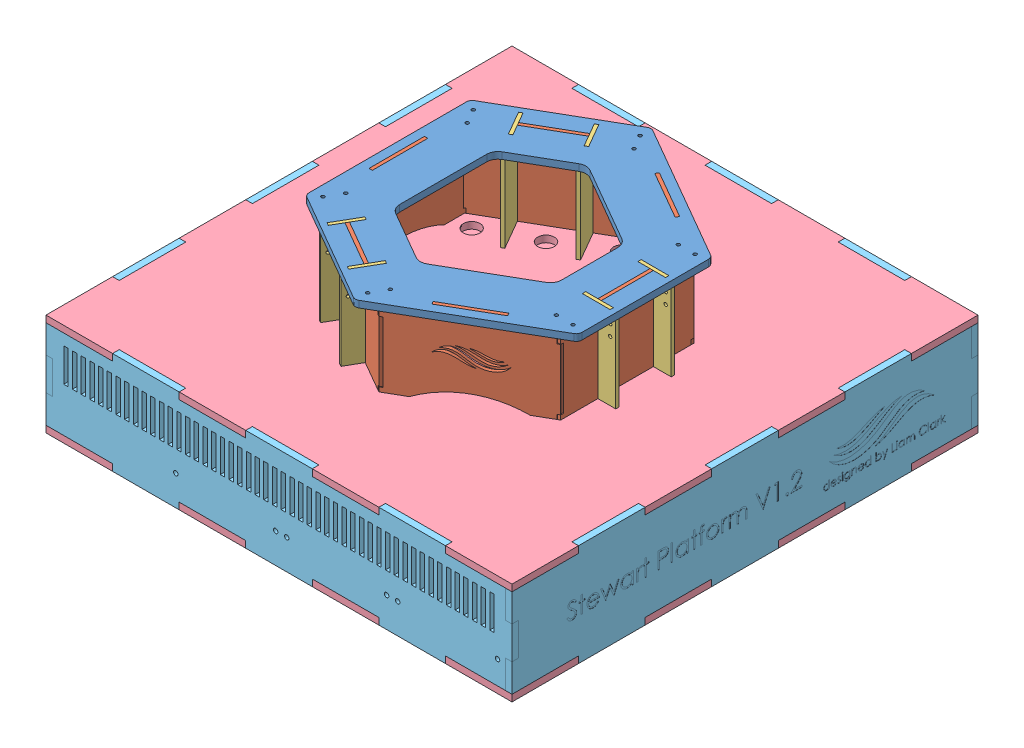
SolidWorks assembly Platform Base Assembly - V1, configuration Default. Lengths in mm.
Overall size (420 167 420).
21 component instances, 6 part files, 64 mates.
Components (placement in the parent):
- Base Platform - V1-1: Base Platform - V1 [Default] at origin size (231.96 6 266.3)
- Base Leg - V1-2: Base Leg - V1 [Default] at (49.3357 0 88.0519) x (0.866025 0 -0.5) z (0.5 0 0.866025) size (120 81 3)
- Base Leg - V1-6: Base Leg - V1 [Default] at (51.5874 0 -86.7519) x (-0.866025 0 -0.5) z (0.5 0 -0.866025) size (120 81 3)
- Base Leg - V1-10: Base Leg - V1 [Default] at (-100.923 0 -1.3) x (0 0 1) z (-1 0 0) size (120 81 3)
- Base Leg Support - V1-1: Base Leg Support - V1 [Default] at (-28.2619 -67.8577 -101.951) x (0.5 0 0.866025) z (-0.866025 0 0.5) size (50 81 3)
- Base Leg Support - V1-2: Base Leg Support - V1 [Default] at (-71.5631 -67.8577 -76.951) x (0.5 0 0.866025) z (-0.866025 0 0.5) size (50 81 3)
- Base Leg Support - V1-4: Base Leg Support - V1 [Default] at (-74.1612 -67.8577 75.451) x (0.5 0 -0.866025) z (0.866025 0 0.5) size (50 81 3)
- Base Leg Support - V1-6: Base Leg Support - V1 [Default] at (-30.8599 -67.8577 100.451) x (0.5 0 -0.866025) z (0.866025 0 0.5) size (50 81 3)
- Base Leg Support - V1-8: Base Leg Support - V1 [Default] at (102.423 -67.8577 26.5) x (-1 0 0) z (0 0 -1) size (50 81 3)
- Base Leg Support - V1-10: Base Leg Support - V1 [Default] at (102.423 -67.8577 -23.5) x (-1 0 0) z (0 0 -1) size (50 81 3)
- Base Leg - V1-13: Base Leg - V1 [Support Leg] at (-51.5874 0 86.7519) x (0.866025 0 0.5) z (-0.5 0 0.866025) size (120 81 3)
- Base Leg - V1-14: Base Leg - V1 [Support Leg] at (100.923 0 1.3) x (0 0 -1) z (1 0 0) size (120 81 3)
- Base Leg - V1-16: Base Leg - V1 [Support Leg] at (-49.3357 0 -88.0519) x (-0.866025 0 0.5) z (-0.5 0 -0.866025) size (120 81 3)
- Platform Base - V1-1: Platform Base - V1 [Top] at (0 -75 0) x (0 0 -1) z (1 0 0) size (420 6 420)
- Base Side Panels - V1-1: Base Side Panels - V1 [Front] at (204 -115 0) x (0 0 -1) z (0 -1 0) size (420 6 92)
- Base Side Panels - V1-2: Base Side Panels - V1 [Side 1] at (0 -115 -204) x (-1 0 0) z (0 -1 0) size (420 6 92)
- Base Side Panels - V1-4: Base Side Panels - V1 [Side 2] at (0 -115 204) x (1 0 0) z (0 -1 0) size (420 6 92)
- Platform Base - V1-2: Platform Base - V1 [Bottom] at (0 -161 0) x (0 0 -1) z (1 0 0) size (420 6 420)
- Center Beam - V1-1: Center Beam - V1 [Default] at (0 -115 3) x (-1 0 0) z (0 -1 0) size (50 6 92)
- Center Beam - V1-2: Center Beam - V1 [Default] at (3 -115 0) x (0 0 -1) z (0 1 0) size (50 6 92)
- Base Side Panels - V1-6: Base Side Panels - V1 [Back] at (-204 -115 0) x (0 0 1) z (0 -1 0) size (420 6 92)
Mates (geometry in assembly coordinates):
- Coincident3: coincident aligned: plane of Base Platform - V1-1 through (0 0 0) normal (1 0 0); plane of assembly through (0 0 0) normal (1 0 0)
- Coincident4: coincident aligned: plane of Base Platform - V1-1 through (0 0 0) normal (0 1 0); plane of assembly through (0 0 0) normal (0 1 0)
- Coincident6: coincident aligned: plane of Base Platform - V1-1 through (0 0 0) normal (0 0 1); plane of assembly through (0 0 0) normal (0 0 1)
- Coincident10: coincident aligned: plane of Base Platform - V1-1 through (0 6 0) normal (0 1 0); plane of Base Leg - V1-2 through (30.3109 6 102.5) normal (0 1 0)
- Coincident11: coincident anti-aligned: plane of Base Platform - V1-1 through (30.3109 0 102.5) normal (0.866025 0 -0.5); plane of Base Leg - V1-2 through (30.3109 6 102.5) normal (-0.866025 0 0.5)
- Coincident12: coincident anti-aligned: plane of Base Platform - V1-1 through (72.1122 0 74.9019) normal (0.5 0 0.866025); plane of Base Leg - V1-2 through (49.3357 0 88.0519) normal (-0.5 0 -0.866025)
- Coincident16: coincident aligned: plane of Base Platform - V1-1 through (0 6 0) normal (0 1 0); plane of Base Leg - V1-6 through (73.6122 6 -77.5) normal (0 1 0)
- Coincident17: coincident anti-aligned: plane of Base Platform - V1-1 through (73.6122 0 -77.5) normal (-0.866025 0 -0.5); plane of Base Leg - V1-6 through (73.6122 6 -77.5) normal (0.866025 0 0.5)
- Coincident18: coincident anti-aligned: plane of Base Platform - V1-1 through (28.8109 0 -99.9019) normal (0.5 0 -0.866025); plane of Base Leg - V1-6 through (51.5874 0 -86.7519) normal (-0.5 0 0.866025)
- Coincident22: coincident aligned: plane of Base Platform - V1-1 through (0 6 0) normal (0 1 0); plane of Base Leg - V1-10 through (-103.923 6 -25) normal (0 1 0)
- Coincident23: coincident anti-aligned: plane of Base Platform - V1-1 through (-103.923 0 -25) normal (0 0 1); plane of Base Leg - V1-10 through (-103.923 6 -25) normal (0 0 -1)
- Coincident24: coincident anti-aligned: plane of Base Platform - V1-1 through (-100.923 0 25) normal (-1 0 0); plane of Base Leg - V1-10 through (-100.923 0 -1.3) normal (1 0 0)
- Coincident27: coincident anti-aligned: plane of Base Platform - V1-1 through (-22.0119 0 -91.1256) normal (-0.866025 0 0.5); plane of Base Leg Support - V1-1 through (-28.2619 -67.8577 -101.951) normal (0.866025 0 -0.5)
- Coincident28: coincident aligned: plane of Base Platform - V1-1 through (0 6 0) normal (0 1 0); plane of Base Leg Support - V1-1 through (-24.6099 6 -89.6256) normal (0 1 0)
- Coincident29: coincident anti-aligned: plane of Base Platform - V1-1 through (-34.5119 0 -112.7763) normal (0.5 0 0.866025); plane of Base Leg Support - V1-1 through (-37.1099 6 -111.2763) normal (-0.5 0 -0.866025)
- Coincident30: coincident anti-aligned: plane of Base Platform - V1-1 through (-65.3131 0 -66.1256) normal (-0.866025 0 0.5); plane of Base Leg Support - V1-2 through (-71.5631 -67.8577 -76.951) normal (0.866025 0 -0.5)
- Coincident31: coincident aligned: plane of Base Platform - V1-1 through (0 6 0) normal (0 1 0); plane of Base Leg Support - V1-2 through (-67.9112 6 -64.6256) normal (0 1 0)
- Coincident32: coincident anti-aligned: plane of Base Platform - V1-1 through (-77.8131 0 -87.7763) normal (0.5 0 0.866025); plane of Base Leg Support - V1-2 through (-80.4112 6 -86.2763) normal (-0.5 0 -0.866025)
- Coincident33: coincident anti-aligned: plane of Base Platform - V1-1 through (-67.9112 0 64.6256) normal (0.866025 0 0.5); plane of Base Leg Support - V1-4 through (-74.1612 -67.8577 75.451) normal (-0.866025 0 -0.5)
- Coincident34: coincident aligned: plane of Base Platform - V1-1 through (0 6 0) normal (0 1 0); plane of Base Leg Support - V1-4 through (-65.3131 6 66.1256) normal (0 1 0)
- Coincident35: coincident anti-aligned: plane of Base Platform - V1-1 through (-80.4112 0 86.2763) normal (0.5 0 -0.866025); plane of Base Leg Support - V1-4 through (-77.8131 6 87.7763) normal (-0.5 0 0.866025)
- Coincident36: coincident anti-aligned: plane of Base Platform - V1-1 through (-24.6099 0 89.6256) normal (0.866025 0 0.5); plane of Base Leg Support - V1-6 through (-30.8599 -67.8577 100.451) normal (-0.866025 0 -0.5)
- Coincident37: coincident aligned: plane of Base Platform - V1-1 through (0 6 0) normal (0 1 0); plane of Base Leg Support - V1-6 through (-22.0119 6 91.1256) normal (0 1 0)
- Coincident38: coincident anti-aligned: plane of Base Platform - V1-1 through (-37.1099 0 111.2763) normal (0.5 0 -0.866025); plane of Base Leg Support - V1-6 through (-34.5119 6 112.7763) normal (-0.5 0 0.866025)
- Coincident39: coincident anti-aligned: plane of Base Platform - V1-1 through (89.923 0 26.5) normal (0 0 -1); plane of Base Leg Support - V1-8 through (102.423 -67.8577 26.5) normal (0 0 1)
- Coincident41: coincident aligned: plane of Base Platform - V1-1 through (0 6 0) normal (0 1 0); plane of Base Leg Support - V1-8 through (89.923 6 23.5) normal (0 1 0)
- Coincident42: coincident anti-aligned: plane of Base Platform - V1-1 through (114.923 0 26.5) normal (-1 0 0); plane of Base Leg Support - V1-8 through (114.923 6 23.5) normal (1 0 0)
- Coincident43: coincident anti-aligned: plane of Base Platform - V1-1 through (89.923 0 -23.5) normal (0 0 -1); plane of Base Leg Support - V1-10 through (102.423 -67.8577 -23.5) normal (0 0 1)
- Coincident44: coincident aligned: plane of Base Platform - V1-1 through (0 6 0) normal (0 1 0); plane of Base Leg Support - V1-10 through (89.923 6 -26.5) normal (0 1 0)
- Coincident45: coincident anti-aligned: plane of Base Platform - V1-1 through (114.923 0 -23.5) normal (-1 0 0); plane of Base Leg Support - V1-10 through (114.923 6 -26.5) normal (1 0 0)
- Coincident46: coincident aligned: plane of Base Platform - V1-1 through (0 6 0) normal (0 1 0); plane of Base Leg - V1-13 through (-73.6122 6 77.5) normal (0 1 0)
- Coincident47: coincident anti-aligned: plane of Base Leg Support - V1-4 through (-71.5631 -67.8577 76.951) normal (0.866025 0 0.5); plane of Base Leg - V1-13 through (-72.3131 6 78.25) normal (-0.866025 0 -0.5)
- Coincident48: coincident anti-aligned: plane of Base Platform - V1-1 through (-28.8109 0 99.9019) normal (-0.5 0 0.866025); plane of Base Leg - V1-13 through (-51.5874 0 86.7519) normal (0.5 0 -0.866025)
- Coincident49: coincident aligned: plane of Base Platform - V1-1 through (0 6 0) normal (0 1 0); plane of Base Leg - V1-14 through (103.923 6 25) normal (0 1 0)
- Coincident50: coincident anti-aligned: plane of Base Leg Support - V1-8 through (102.423 -67.8577 23.5) normal (0 0 -1); plane of Base Leg - V1-14 through (103.923 6 23.5) normal (0 0 1)
- Coincident51: coincident anti-aligned: plane of Base Platform - V1-1 through (100.923 0 -25) normal (1 0 0); plane of Base Leg - V1-14 through (100.923 0 1.3) normal (-1 0 0)
- Coincident52: coincident aligned: plane of Base Platform - V1-1 through (0 6 0) normal (0 1 0); plane of Base Leg - V1-16 through (-30.3109 6 -102.5) normal (0 1 0)
- Coincident53: coincident anti-aligned: plane of Base Leg Support - V1-1 through (-30.8599 -67.8577 -100.451) normal (-0.866025 0 0.5); plane of Base Leg - V1-16 through (-31.6099 6 -101.75) normal (0.866025 0 -0.5)
- Coincident54: coincident anti-aligned: plane of Base Platform - V1-1 through (-72.1122 0 -74.9019) normal (-0.5 0 -0.866025); plane of Base Leg - V1-16 through (-49.3357 0 -88.0519) normal (0.5 0 0.866025)
- Coincident55: coincident anti-aligned: plane of Base Leg Support - V1-10 through (102.423 -67.8577 -26.5) normal (0 0 -1); plane of Platform Base - V1-1 through (103.923 -75 -26.5) normal (0 0 1)
- Coincident56: coincident anti-aligned: plane of Base Leg Support - V1-10 through (120.003 0 -26.5) normal (1 0 0); plane of Platform Base - V1-1 through (120.003 -75 -26.5) normal (-1 0 0)
- Coincident57: coincident aligned: plane of Base Leg Support - V1-10 through (120.003 -75 -26.5) normal (0 -1 0); plane of Platform Base - V1-1 through (0 -75 0) normal (0 -1 0)
- Coincident58: coincident aligned: plane of Platform Base - V1-1 through (0 -69 0) normal (0 1 0); plane of Base Side Panels - V1-1 through (210 -69 -210) normal (0 1 0)
- Coincident59: coincident aligned: plane of Platform Base - V1-1 through (210 -69 210) normal (1 0 0); plane of Base Side Panels - V1-1 through (210 -115 0) normal (1 0 0)
- Coincident61: coincident aligned: plane of Platform Base - V1-1 through (0 -69 0) normal (0 1 0); plane of Base Side Panels - V1-2 through (-210 -69 -210) normal (0 1 0)
- Coincident62: coincident anti-aligned: plane of Base Side Panels - V1-1 through (204 -115 0) normal (-1 0 0); plane of Base Side Panels - V1-2 through (204 -100.1721 -204) normal (1 0 0)
- Coincident63: coincident aligned: plane of Platform Base - V1-1 through (210 -69 -210) normal (0 0 -1); plane of Base Side Panels - V1-2 through (0 -115 -210) normal (0 0 -1)
- Coincident67: coincident aligned: plane of Platform Base - V1-1 through (210 -69 210) normal (0 0 1); plane of Base Side Panels - V1-4 through (0 -115 210) normal (0 0 1)
- Coincident68: coincident aligned: plane of Platform Base - V1-1 through (0 -69 0) normal (0 1 0); plane of Base Side Panels - V1-4 through (210 -69 210) normal (0 1 0)
- Coincident69: coincident aligned: plane of Base Side Panels - V1-1 through (210 -115 0) normal (1 0 0); plane of Base Side Panels - V1-4 through (210 -161 210) normal (1 0 0)
- Coincident70: coincident aligned: plane of Base Side Panels - V1-1 through (210 -115 0) normal (1 0 0); plane of Platform Base - V1-2 through (210 -155 210) normal (1 0 0)
- Coincident71: coincident anti-aligned: plane of Base Side Panels - V1-1 through (204 -155 90) normal (0 -1 0); plane of Platform Base - V1-2 through (0 -155 0) normal (0 1 0)
- Coincident72: coincident aligned: plane of Base Side Panels - V1-4 through (0 -115 210) normal (0 0 1); plane of Platform Base - V1-2 through (210 -155 210) normal (0 0 1)
- Coincident73: coincident aligned: plane of Platform Base - V1-2 through (0 -161 0) normal (0 -1 0); plane of Center Beam - V1-1 through (15 -161 -3) normal (0 -1 0)
- Coincident74: coincident anti-aligned: plane of Platform Base - V1-2 through (-3 -161 -3) normal (0 0 1); plane of Center Beam - V1-1 through (0 -115 -3) normal (0 0 -1)
- Coincident75: coincident anti-aligned: plane of Platform Base - V1-2 through (-15 -161 3) normal (1 0 0); plane of Center Beam - V1-1 through (-15 -155 -3) normal (-1 0 0)
- Coincident76: coincident aligned: plane of Platform Base - V1-1 through (0 -69 0) normal (0 1 0); plane of Center Beam - V1-2 through (-3 -69 15) normal (0 1 0)
- Coincident79: coincident anti-aligned: plane of Center Beam - V1-1 through (0 -115 -3) normal (0 0 -1); plane of Center Beam - V1-2 through (3 -115 -3) normal (0 0 1)
- Coincident80: coincident aligned: plane of Platform Base - V1-1 through (0 -69 0) normal (0 1 0); plane of Center Beam - V1-2 through (-3 -69 15) normal (0 1 0)
- Coincident81: coincident anti-aligned: plane of Center Beam - V1-1 through (3 -115 3) normal (-1 0 0); plane of Center Beam - V1-2 through (3 -115 0) normal (1 0 0)
- Coincident82: coincident aligned: plane of Base Side Panels - V1-1 through (210 -161 -210) normal (0 0 -1); plane of Base Side Panels - V1-2 through (0 -115 -210) normal (0 0 -1)
- Coincident87: coincident: plane of Platform Base - V1-1 through (-210 -69 210) normal (-1 0 0); plane of Base Side Panels - V1-6 through (-210 -138.9693 0) normal (-1 0 0)
- Coincident89: coincident: plane of Base Side Panels - V1-4 through (0 -115 210) normal (0 0 1); plane of Base Side Panels - V1-6 through (-210 -161 210) normal (0 0 1)
- Coincident90: coincident aligned: plane of Platform Base - V1-1 through (0 -69 0) normal (0 1 0); plane of Base Side Panels - V1-6 through (-210 -69 210) normal (0 1 0)
